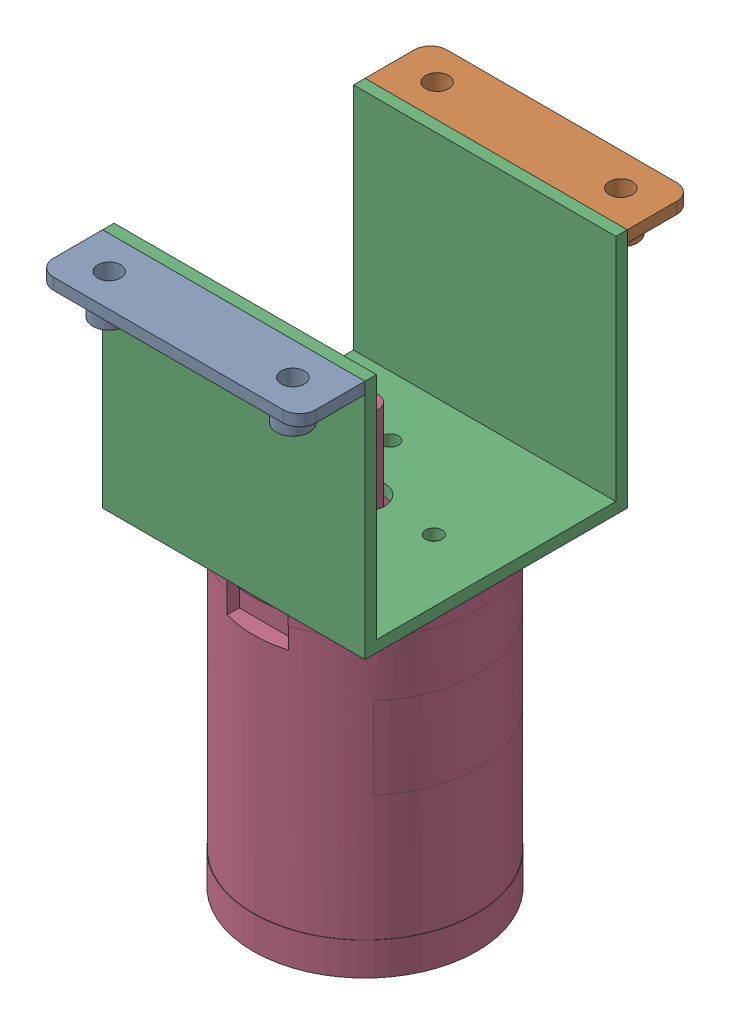
SolidWorks assembly Moter Mount asssembly v2, configuration Default. Lengths in mm.
Overall size (80 184 120).
2 component instances, 2 part files, 3 mates.
Components (placement in the parent):
- MY6812 Moter mount  v2-1: MY6812 Moter mount  v2 [Default] at (0.2306 -11.3583 7.595) size (80 73.5 120)
- my6812 moter-1: my6812 moter [Predeterminado] at (0.2306 -61.3583 7.595) x (1 0 0) z (0 1 0) size (68.2 68.2 138.5)
Mates (geometry in assembly coordinates):
- Concentric1: concentric: circle of MY6812 Moter mount  v2-1; circle of my6812 moter-1
- Concentric2: concentric: circle of MY6812 Moter mount  v2-1; circle of my6812 moter-1
- Coincident1: coincident anti-aligned: plane of MY6812 Moter mount  v2-1 through (0.2306 -11.3583 7.595) normal (0 -1 0); plane of my6812 moter-1 through (0.2306 -90.1147 7.595) normal (0 1 0)
